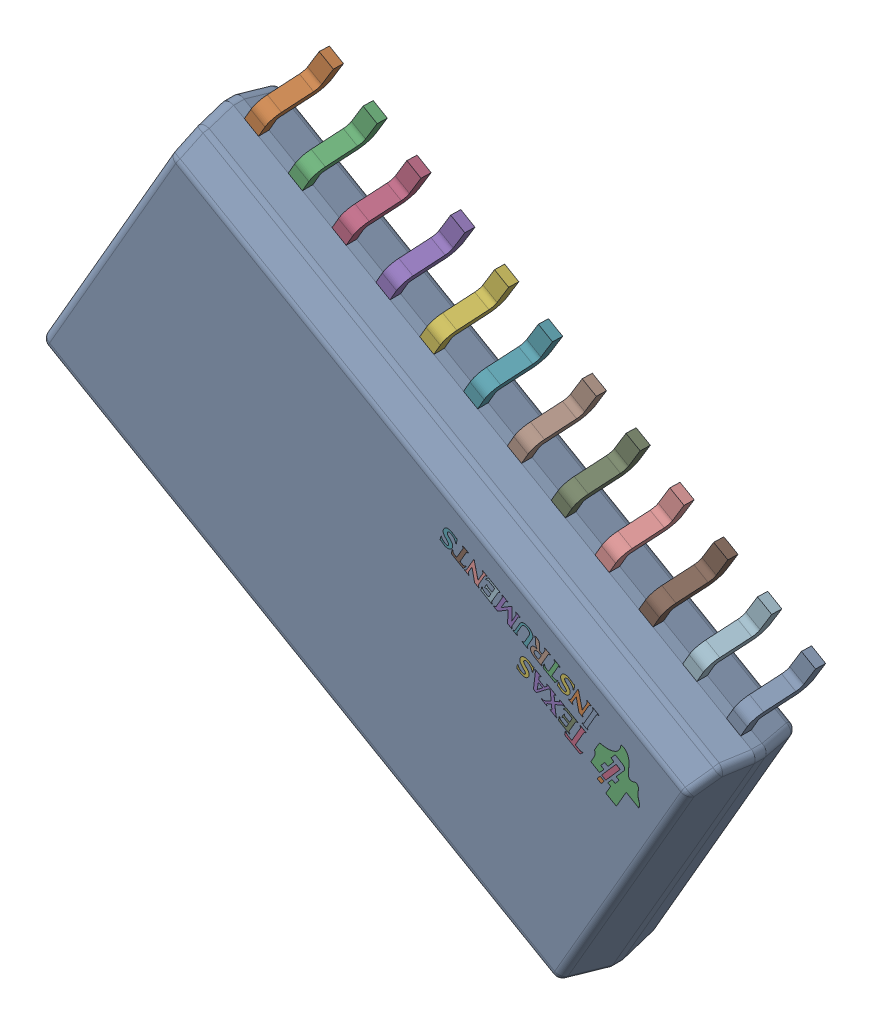
SolidWorks assembly U2, configuration Défaut. Lengths in mm.
Overall size (18.51 16.65 2.65).
28 component instances, 4 part files, 0 mates.
Components (placement in the parent):
- IC_Texas_Instruments_CD74HC4067M96_eec-1: IC_Texas_Instruments_CD74HC4067M96_eec [Défaut] at (-22.368 19.247 0) x (0.5 0.866025 0) z (0 0 1) size (10.34 15.4 2.65)
  - BODY-SO-1: BODY-SO [Défaut] at (0 0 1.0825) x (0 1 0) z (1 0 0) size (15.4 2.45 7.5)
  - LEAD-SO-1: LEAD-SO [Défaut] at (4.315 6.985 0.25) x (0 1 0) z (1 0 0) size (0.41 1.43 1.42)
  - LEAD-SO-2: LEAD-SO [Défaut] at (4.315 5.715 0.25) x (0 1 0) z (1 0 0) size (0.41 1.43 1.42)
  - LEAD-SO-3: LEAD-SO [Défaut] at (4.315 4.445 0.25) x (0 1 0) z (1 0 0) size (0.41 1.43 1.42)
  - LEAD-SO-4: LEAD-SO [Défaut] at (4.315 3.175 0.25) x (0 1 0) z (1 0 0) size (0.41 1.43 1.42)
  - LEAD-SO-5: LEAD-SO [Défaut] at (4.315 1.905 0.25) x (0 1 0) z (1 0 0) size (0.41 1.43 1.42)
  - LEAD-SO-6: LEAD-SO [Défaut] at (4.315 0.635 0.25) x (0 1 0) z (1 0 0) size (0.41 1.43 1.42)
  - LEAD-SO-7: LEAD-SO [Défaut] at (4.315 -0.635 0.25) x (0 1 0) z (1 0 0) size (0.41 1.43 1.42)
  - LEAD-SO-8: LEAD-SO [Défaut] at (4.315 -1.905 0.25) x (0 1 0) z (1 0 0) size (0.41 1.43 1.42)
  - LEAD-SO-9: LEAD-SO [Défaut] at (4.315 -3.175 0.25) x (0 1 0) z (1 0 0) size (0.41 1.43 1.42)
  - LEAD-SO-10: LEAD-SO [Défaut] at (4.315 -4.445 0.25) x (0 1 0) z (1 0 0) size (0.41 1.43 1.42)
  - LEAD-SO-11: LEAD-SO [Défaut] at (4.315 -5.715 0.25) x (0 1 0) z (1 0 0) size (0.41 1.43 1.42)
  - LEAD-SO-12: LEAD-SO [Défaut] at (4.315 -6.985 0.25) x (0 1 0) z (1 0 0) size (0.41 1.43 1.42)
  - LEAD-SO-13: LEAD-SO [Défaut] at (-4.315 6.985 0.25) x (0 -1 0) z (-1 0 0) size (0.41 1.43 1.42)
  - LEAD-SO-14: LEAD-SO [Défaut] at (-4.315 5.715 0.25) x (0 -1 0) z (-1 0 0) size (0.41 1.43 1.42)
  - LEAD-SO-15: LEAD-SO [Défaut] at (-4.315 4.445 0.25) x (0 -1 0) z (-1 0 0) size (0.41 1.43 1.42)
  - LEAD-SO-16: LEAD-SO [Défaut] at (-4.315 3.175 0.25) x (0 -1 0) z (-1 0 0) size (0.41 1.43 1.42)
  - LEAD-SO-17: LEAD-SO [Défaut] at (-4.315 1.905 0.25) x (0 -1 0) z (-1 0 0) size (0.41 1.43 1.42)
  - LEAD-SO-18: LEAD-SO [Défaut] at (-4.315 0.635 0.25) x (0 -1 0) z (-1 0 0) size (0.41 1.43 1.42)
  - LEAD-SO-19: LEAD-SO [Défaut] at (-4.315 -0.635 0.25) x (0 -1 0) z (-1 0 0) size (0.41 1.43 1.42)
  - LEAD-SO-20: LEAD-SO [Défaut] at (-4.315 -1.905 0.25) x (0 -1 0) z (-1 0 0) size (0.41 1.43 1.42)
  - LEAD-SO-21: LEAD-SO [Défaut] at (-4.315 -3.175 0.25) x (0 -1 0) z (-1 0 0) size (0.41 1.43 1.42)
  - LEAD-SO-22: LEAD-SO [Défaut] at (-4.315 -4.445 0.25) x (0 -1 0) z (-1 0 0) size (0.41 1.43 1.42)
  - LEAD-SO-23: LEAD-SO [Défaut] at (-4.315 -5.715 0.25) x (0 -1 0) z (-1 0 0) size (0.41 1.43 1.42)
  - LEAD-SO-24: LEAD-SO [Défaut] at (-4.315 -6.985 0.25) x (0 -1 0) z (-1 0 0) size (0.41 1.43 1.42)
  - Texas Logo Yury-1: Texas Logo Yury [Défaut] at (2.174 -7.1221 2.551) x (0 1 0) z (0 0 1) size (1.32 1.29 0.11)
  - Texas Logo Yury - Copy-1: Texas Logo Yury - Copy [Défaut] at (2.0641 -7.1534 2.551) x (0 1 0) z (0 0 1) size (4.61 1.2 0.1)
